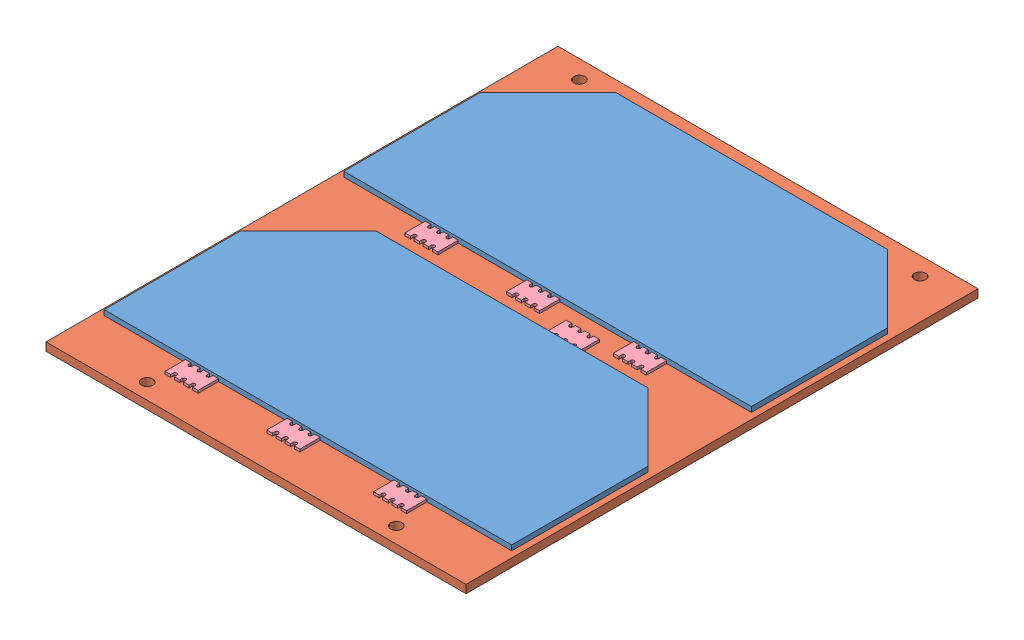
SolidWorks assembly B3_-Y_panel, configuration Default. Lengths in mm.
Overall size (82.6 7.1 100.7).
11 component instances, 4 part files, 29 mates.
Components (placement in the parent):
- Solar panel-1: Solar panel [Default] at (-43.4703 -35.5175 64.7205) size (80.15 1 40.15)
- Solar panel-2: Solar panel [Default] at (-69.4046 -34.5175 111.8705) x (-1 0 0) z (0 0 1) size (80.15 1 40.15)
- B3_±Y_panel-2: B3_±Y_panel [Default] at (-32.6974 -37.1175 99.3411) x (-1 0 0) z (0 0 -1) size (82.6 1.6 100.7)
- Solar panel_f-1: Solar panel_f [Default] at (-68.4374 -41.6175 123.2036) x (0 0 -1) z (-1 0 0) size (3.7 4.5 24)
- Solar panel_connector-1: Solar panel_connector [Default] at (-74.0124 -35.5175 74.5536) size (6.5 0.5 4)
- Solar panel_connector-2: Solar panel_connector [Default] at (-74.0124 -35.5175 121.7036) size (6.5 0.5 4)
- Solar panel_connector-3: Solar panel_connector [Default] at (-54.0124 -35.5175 121.7036) size (6.5 0.5 4)
- Solar panel_connector-4: Solar panel_connector [Default] at (-33.0124 -35.5175 121.7036) size (6.5 0.5 4)
- Solar panel_connector-5: Solar panel_connector [Default] at (-33.0124 -35.5175 74.5536) size (6.5 0.5 4)
- Solar panel_connector-6: Solar panel_connector [Default] at (-54.0124 -35.5175 74.5536) size (6.5 0.5 4)
- Solar panel_connector-7: Solar panel_connector [Default] at (-43.2624 -35.5175 77.5536) size (6.5 0.5 4)
Mates (geometry in assembly coordinates):
- Coincident1: coincident aligned: plane of Solar panel-1 through (-43.4703 -34.5175 64.7205) normal (0 1 0); plane of Solar panel-2 through (-69.4046 -34.5175 111.8705) normal (0 1 0)
- Coincident25: coincident anti-aligned: plane of Solar panel-1 through (-43.4703 -35.5175 64.7205) normal (0 -1 0); plane of B3_±Y_panel-2 through (-32.6974 -35.5175 99.3411) normal (0 1 0)
- Coincident26: coincident anti-aligned: plane of B3_±Y_panel-2 through (-32.6974 -37.1175 99.3411) normal (0 -1 0); plane of Solar panel_f-1 through (-68.4374 -37.1175 123.2036) normal (0 1 0)
- Coincident34: coincident aligned: plane of Solar panel-1 through (-96.5124 -34.5175 74.5536) normal (-1 0 0); plane of Solar panel-2 through (-96.5124 -35.5175 94.9036) normal (-1 0 0)
- Distance9: distance = 8.7 mm aligned: plane of Solar panel_f-1 through (-44.4374 -41.6175 123.2036) normal (0 0 1); plane of B3_±Y_panel-2 through (-14.9374 -35.5175 131.9036) normal (0 0 1)
- Distance12: distance = 1.225 mm aligned: plane of Solar panel-1 through (-96.5124 -34.5175 74.5536) normal (-1 0 0); plane of B3_±Y_panel-2 through (-97.7374 -35.5175 31.2036) normal (-1 0 0)
- Distance13: distance = 29.3 mm aligned: plane of Solar panel_f-1 through (-68.4374 -41.6175 123.2036) normal (-1 0 0); plane of B3_±Y_panel-2 through (-97.7374 -35.5175 31.2036) normal (-1 0 0)
- Distance15: distance = 3.2 mm aligned: plane of Solar panel-1 through (-83.1624 -34.5175 34.4036) normal (0 0 -1); plane of B3_±Y_panel-2 through (-97.9374 -35.5175 31.2036) normal (0 0 -1)
- 一致1: coincident anti-aligned: plane of B3_±Y_panel-2 through (-32.6974 -35.5175 99.3411) normal (0 1 0); plane of Solar panel_connector-1 through (-75.4624 -35.5175 78.0536) normal (0 -1 0)
- 一致2: coincident anti-aligned: plane of B3_±Y_panel-2 through (-32.6974 -35.5175 99.3411) normal (0 1 0); plane of Solar panel_connector-7 through (-44.7124 -35.5175 81.0536) normal (0 -1 0)
- 一致3: coincident anti-aligned: plane of B3_±Y_panel-2 through (-32.6974 -35.5175 99.3411) normal (0 1 0); plane of Solar panel_connector-6 through (-55.4624 -35.5175 78.0536) normal (0 -1 0)
- 一致4: coincident anti-aligned: plane of B3_±Y_panel-2 through (-32.6974 -35.5175 99.3411) normal (0 1 0); plane of Solar panel_connector-5 through (-34.4624 -35.5175 78.0536) normal (0 -1 0)
- 一致5: coincident anti-aligned: plane of B3_±Y_panel-2 through (-32.6974 -35.5175 99.3411) normal (0 1 0); plane of Solar panel_connector-4 through (-34.4624 -35.5175 125.2036) normal (0 -1 0)
- 一致9: coincident anti-aligned: plane of B3_±Y_panel-2 through (-32.6974 -35.5175 99.3411) normal (0 1 0); plane of Solar panel_connector-3 through (-55.4624 -35.5175 125.2036) normal (0 -1 0)
- 一致10: coincident anti-aligned: plane of B3_±Y_panel-2 through (-32.6974 -35.5175 99.3411) normal (0 1 0); plane of Solar panel_connector-2 through (-75.4624 -35.5175 125.2036) normal (0 -1 0)
- 距離1: distance = 16 mm: plane of Solar panel-1 through (-96.5124 -34.5175 74.5536) normal (-1 0 0); line of Solar panel_connector-1 through (-80.5124 -35.0175 74.5536) axis (0 0 1)
- 一致14: coincident anti-aligned: plane of Solar panel-1 through (-16.3624 -34.5175 74.5536) normal (0 0 1); plane of Solar panel_connector-1 through (-77.6124 -35.0175 74.5536) normal (0 0 -1)
- 距離2: distance = 36 mm: line of Solar panel-1 through (-96.5124 -34.5175 47.7536) axis (0 0 1); plane of Solar panel_connector-6 through (-60.5124 -35.0175 74.5536) normal (-1 0 0)
- 一致16: coincident anti-aligned: plane of Solar panel-1 through (-16.3624 -34.5175 74.5536) normal (0 0 1); plane of Solar panel_connector-6 through (-57.6124 -35.0175 74.5536) normal (0 0 -1)
- 距離4: distance = 57 mm aligned: plane of Solar panel-1 through (-96.5124 -34.5175 74.5536) normal (-1 0 0); plane of Solar panel_connector-5 through (-39.5124 -35.0175 74.5536) normal (-1 0 0)
- 一致21: coincident anti-aligned: plane of Solar panel-1 through (-16.3624 -34.5175 74.5536) normal (0 0 1); plane of Solar panel_connector-5 through (-35.9124 -35.0175 74.5536) normal (0 0 -1)
- 一致23: coincident aligned: line of Solar panel_connector-1 through (-80.5124 -35.0175 74.5536) axis (0 0 1); line of Solar panel_connector-2 through (-80.5124 -35.0175 121.7036) axis (0 0 1)
- 一致24: coincident anti-aligned: plane of Solar panel-2 through (-96.5124 -35.5175 121.7036) normal (0 0 1); plane of Solar panel_connector-2 through (-76.9124 -35.0175 121.7036) normal (0 0 -1)
- 一致25: coincident aligned: line of Solar panel_connector-3 through (-60.5124 -35.0175 121.7036) axis (0 0 1); line of Solar panel_connector-6 through (-60.5124 -35.0175 74.5536) axis (0 0 1)
- 一致26: coincident anti-aligned: plane of Solar panel-2 through (-96.5124 -35.5175 121.7036) normal (0 0 1); plane of Solar panel_connector-3 through (-56.9124 -35.0175 121.7036) normal (0 0 -1)
- 一致27: coincident: line of Solar panel_connector-4 through (-39.5124 -35.0175 121.7036) axis (0 0 1); plane of Solar panel_connector-5 through (-39.5124 -35.0175 74.5536) normal (-1 0 0)
- 一致28: coincident anti-aligned: plane of Solar panel-2 through (-96.5124 -35.5175 121.7036) normal (0 0 1); plane of Solar panel_connector-4 through (-35.9124 -35.0175 121.7036) normal (0 0 -1)
- 一致29: coincident anti-aligned: plane of Solar panel-2 through (-29.7124 -35.5175 81.5536) normal (0 0 -1); plane of Solar panel_connector-7 through (-48.6624 -35.0175 81.5536) normal (0 0 1)
- 距離5: distance = 46.75 mm: line of Solar panel_connector-7 through (-49.7624 -35.0175 77.5536) axis (0 0 1); plane of Solar panel-2 through (-96.5124 -35.5175 94.9036) normal (-1 0 0)
